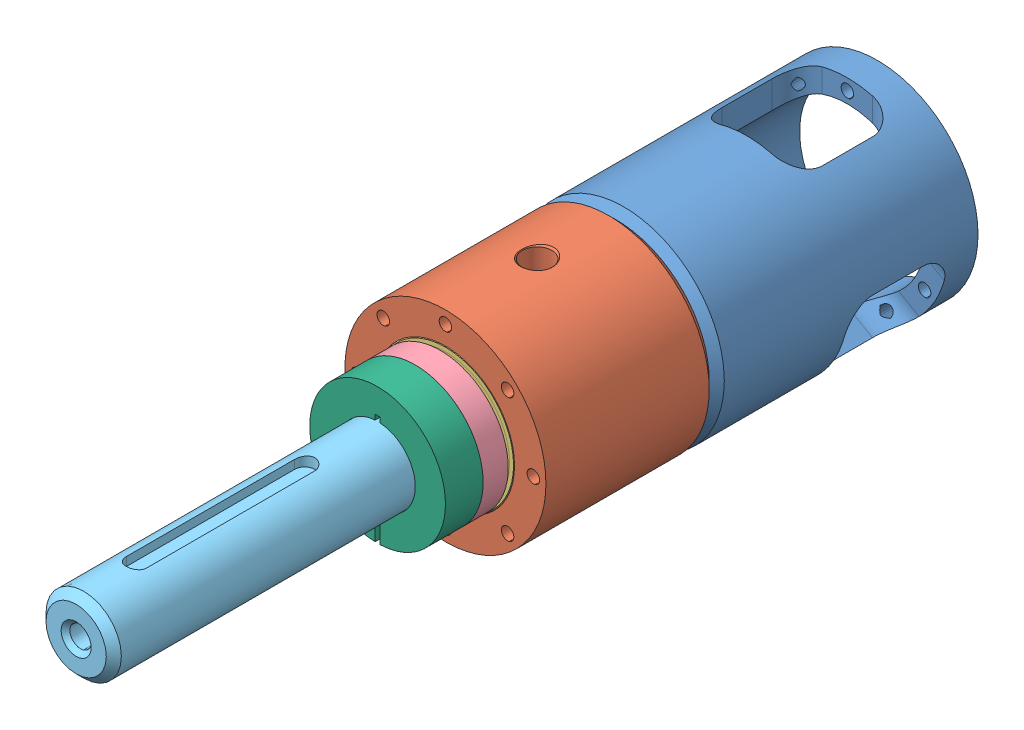
SolidWorks assembly EXTPRO-V1 1120.00-A Bearing Body & Shaft, configuration Default. Lengths in mm.
Overall size (80 80 319).
10 component instances, 7 part files, 14 mates.
Components (placement in the parent):
- EXTPRO-V1 1121.00-A Bearing body-2: EXTPRO-V1 1121.00-A Bearing body [Default] at origin size (80 80 172)
  - EXTPRO-V1 1121.01-A Transition Piece-2: EXTPRO-V1 1121.01-A Transition Piece [Default] at origin size (80 80 104)
  - EXTPRO-V1 1121.02-A Bearing body-2: EXTPRO-V1 1121.02-A Bearing body [Default] at origin size (80 80 73)
- EXTPRO-V1 02 Bearing seal-din3760-as_42x55x8-fkm-3: EXTPRO-V1 02 Bearing seal-din3760-as_42x55x8-fkm [Default] at (0 0 -153.6667) x (0 0 1) z (-0.999137 -0.04153 0) size (8 55 55)
- EXTPRO-V1 02 Bearing seal-din3760-as_42x55x8-fkm-4: EXTPRO-V1 02 Bearing seal-din3760-as_42x55x8-fkm [Default] at (0 0 -213.3333) x (0 0 -1) z (-0.813713 -0.581266 0) size (8 55 55)
- EXTPRO-V1 1120.01-A Seal bearing spacer-2: EXTPRO-V1 1120.01-A Seal bearing spacer [Default] at origin size (54 54 19)
- EXTPRO-V1 1120.02-A Coupling Shaft-2: EXTPRO-V1 1120.02-A Coupling Shaft [Default] at origin size (60 60 270)
- EXTPRO-V1 03 Shaft Clamp-2: EXTPRO-V1 03 Shaft Clamp [Default] at origin size (54 53.98 15)
- EXTPRO-V1 04 Tapered bearing 32006X-5: EXTPRO-V1 04 Tapered bearing 32006X [6677K58] at (0 0 -162.5) x (0.996758 -0.080464 0) z (0 0 1) size (55 55 17.29)
- EXTPRO-V1 04 Tapered bearing 32006X-6: EXTPRO-V1 04 Tapered bearing 32006X [6677K58] at (0 0 -204.5) x (-0.889911 -0.456134 0) z (0 0 -1) size (55 55 17.29)
Mates (geometry in assembly coordinates):
- Concentric1: concentric: cylinder of EXTPRO-V1 1121.00-A Bearing body-2/EXTPRO-V1 1121.02-A Bearing body-2 through (0 0 0) axis (0 0 1) radius 27.5; cylinder of EXTPRO-V1 04 Tapered bearing 32006X-5 through (0 0 -154) axis (0 0 1) radius 27.5
- Concentric2: concentric: cylinder of EXTPRO-V1 1121.00-A Bearing body-2/EXTPRO-V1 1121.02-A Bearing body-2 through (0 0 0) axis (0 0 1) radius 27.5; cylinder of EXTPRO-V1 04 Tapered bearing 32006X-6 through (0 0 -213) axis (0 0 -1) radius 27.5
- Coincident1: coincident: plane of EXTPRO-V1 1121.00-A Bearing body-2/EXTPRO-V1 1121.02-A Bearing body-2 through (0 0 -196) normal (0 0 -1); plane of EXTPRO-V1 04 Tapered bearing 32006X-6 through (-6.842 13.3487 -196) normal (0 0 1)
- Coincident2: coincident: plane of EXTPRO-V1 1121.00-A Bearing body-2/EXTPRO-V1 1121.02-A Bearing body-2 through (0 0 -171) normal (0 0 1); plane of EXTPRO-V1 04 Tapered bearing 32006X-5 through (1.207 14.9514 -171) normal (0 0 -1)
- Concentric3: concentric: cylinder of EXTPRO-V1 1121.00-A Bearing body-2/EXTPRO-V1 1121.02-A Bearing body-2 through (0 0 0) axis (0 0 1) radius 27.5; cylinder of EXTPRO-V1 02 Bearing seal-din3760-as_42x55x8-fkm-3 through (0 0 -153.6667) axis (0 0 -1) radius 27.5
- Coincident4: coincident: plane of EXTPRO-V1 1121.00-A Bearing body-2/EXTPRO-V1 1121.02-A Bearing body-2 through (0 0 -147) normal (0 0 1); plane of EXTPRO-V1 02 Bearing seal-din3760-as_42x55x8-fkm-3 through (-1.1255 27.0766 -147) normal (0 0 1)
- Concentric4: concentric: cylinder of EXTPRO-V1 1121.00-A Bearing body-2/EXTPRO-V1 1121.02-A Bearing body-2 through (0 0 0) axis (0 0 1) radius 27.5; cylinder of EXTPRO-V1 02 Bearing seal-din3760-as_42x55x8-fkm-4 through (0 0 -213.3333) axis (0 0 1) radius 27.5
- Coincident5: coincident: plane of EXTPRO-V1 1121.00-A Bearing body-2/EXTPRO-V1 1121.02-A Bearing body-2 through (0 0 -220) normal (0 0 -1); plane of EXTPRO-V1 02 Bearing seal-din3760-as_42x55x8-fkm-4 through (15.7523 -22.0516 -220) normal (0 0 -1)
- Concentric5: concentric: cylinder of EXTPRO-V1 04 Tapered bearing 32006X-6 through (0 0 -213) axis (0 0 -1) radius 15; cylinder of EXTPRO-V1 1120.02-A Coupling Shaft-2 through (0 0 0) axis (0 0 1) radius 15
- Coincident6: coincident: plane of EXTPRO-V1 04 Tapered bearing 32006X-6 through (-7.7554 15.1307 -213) normal (0 0 -1); plane of EXTPRO-V1 1120.02-A Coupling Shaft-2 through (0 0 -213) normal (0 0 1)
- Concentric6: concentric: cylinder of EXTPRO-V1 1120.02-A Coupling Shaft-2 through (0 0 0) axis (0 0 1) radius 15; cylinder of EXTPRO-V1 1120.01-A Seal bearing spacer-2 through (0 0 0) axis (0 0 1) radius 15
- Coincident7: coincident: plane of EXTPRO-V1 04 Tapered bearing 32006X-5 through (1.3681 16.9473 -154) normal (0 0 1); plane of EXTPRO-V1 1120.01-A Seal bearing spacer-2 through (0 0 -154) normal (0 0 -1)
- Concentric7: concentric: cylinder of EXTPRO-V1 1120.02-A Coupling Shaft-2 through (0 0 0) axis (0 0 1) radius 15; cylinder of EXTPRO-V1 03 Shaft Clamp-2 through (0 0 -120) axis (0 0 -1) radius 15
- Coincident8: coincident: plane of EXTPRO-V1 1120.01-A Seal bearing spacer-2 through (0 0 -135) normal (0 0 1); plane of EXTPRO-V1 03 Shaft Clamp-2 through (0 0 -135) normal (0 0 -1)
